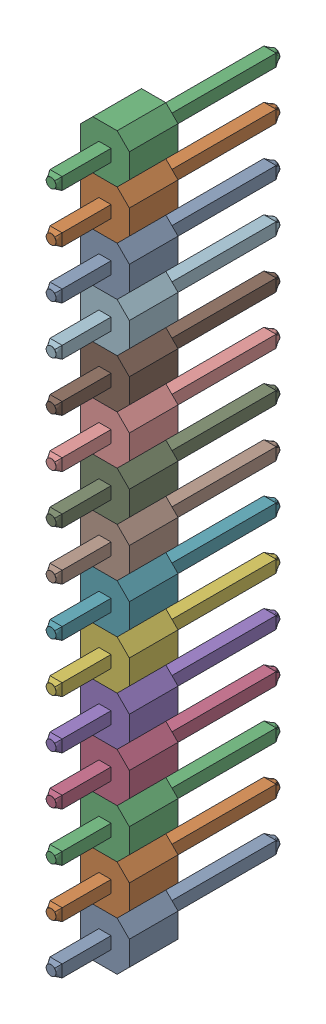
SolidWorks assembly Male Header 15 Pin, configuration Default. Lengths in mm.
Overall size (2.54 38.1 11.76).
15 component instances, 1 part files, 0 mates.
Components (placement in the parent):
- Male Header Pin-1: Male Header Pin [Default] at (-69.8511 8.6783 31.142) size (2.54 2.54 11.76)
- Male Header Pin-2: Male Header Pin [Default] at (-69.8511 11.2183 31.142) size (2.54 2.54 11.76)
- Male Header Pin-3: Male Header Pin [Default] at (-69.8511 13.7583 31.142) size (2.54 2.54 11.76)
- Male Header Pin-4: Male Header Pin [Default] at (-69.8511 16.2983 31.142) size (2.54 2.54 11.76)
- Male Header Pin-5: Male Header Pin [Default] at (-69.8511 18.8383 31.142) size (2.54 2.54 11.76)
- Male Header Pin-6: Male Header Pin [Default] at (-69.8511 21.3783 31.142) size (2.54 2.54 11.76)
- Male Header Pin-7: Male Header Pin [Default] at (-69.8511 23.9183 31.142) size (2.54 2.54 11.76)
- Male Header Pin-8: Male Header Pin [Default] at (-69.8511 26.4583 31.142) size (2.54 2.54 11.76)
- Male Header Pin-9: Male Header Pin [Default] at (-69.8511 28.9983 31.142) size (2.54 2.54 11.76)
- Male Header Pin-10: Male Header Pin [Default] at (-69.8511 31.5383 31.142) size (2.54 2.54 11.76)
- Male Header Pin-11: Male Header Pin [Default] at (-69.8511 34.0783 31.142) size (2.54 2.54 11.76)
- Male Header Pin-12: Male Header Pin [Default] at (-69.8511 36.6183 31.142) size (2.54 2.54 11.76)
- Male Header Pin-13: Male Header Pin [Default] at (-69.8511 39.1583 31.142) size (2.54 2.54 11.76)
- Male Header Pin-14: Male Header Pin [Default] at (-69.8511 41.6983 31.142) size (2.54 2.54 11.76)
- Male Header Pin-15: Male Header Pin [Default] at (-69.8511 44.2383 31.142) size (2.54 2.54 11.76)
